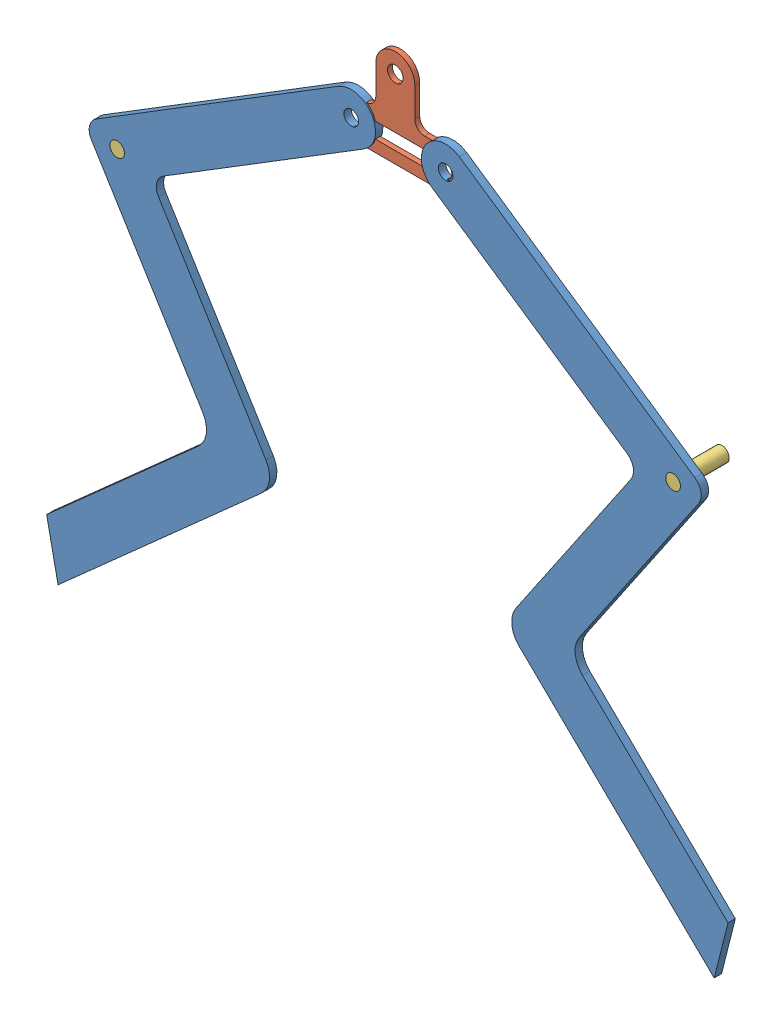
SolidWorks assembly Stopping Mechanism, configuration Default. Lengths in mm.
Overall size (215.56 131.52 10).
5 component instances, 3 part files, 10 mates.
Components (placement in the parent):
- Stop link-1: Stop link [Default] at (11.0323 -18.2674 0) x (0.716751 -0.69733 0) z (0 0 1) size (125 59.52 1.5)
- Linking link-2: Linking link [Default] at (-11.5672 55.4091 0) x (0 0 -1) z (1 0 0) size (1 20 28)
- Stop link-2: Stop link [Default] at (-35.6231 -17.6641 0) x (-0.746853 -0.664989 0) z (0 0 -1) size (125 59.52 1.5)
- pin-1: pin [Default] at (45.621 23.7108 -9.25) size (3 3 10)
- pin-2: pin [Default] at (-68.3239 25.801 0.75) x (-0.173648 0.984808 0) z (0 0 -1) size (3 3 10)
Mates (geometry in assembly coordinates):
- Concentric7: concentric aligned: cylinder of Stop link-1 through (45.621 23.7108 0.75) axis (0 0 -1) radius 1.5; cylinder of pin-1 through (45.621 23.7108 0.75) axis (0 0 -1) radius 1.5
- Concentric8: concentric aligned: cylinder of Stop link-2 through (-68.3239 25.801 -0.75) axis (0 0 1) radius 1.5; cylinder of pin-2 through (-68.3239 25.801 -9.25) axis (0 0 1) radius 1.5
- Coincident6: coincident aligned: plane of Stop link-2 through (-42.0815 -16.7198 0.75) normal (0 0 1); plane of pin-2 through (-68.3239 25.801 0.75) normal (0 0 1)
- Coincident7: coincident aligned: plane of Stop link-1 through (17.526 -17.6093 0.75) normal (0 0 1); plane of pin-1 through (45.621 23.7108 0.75) normal (0 0 1)
- Width1: width anti-aligned: plane of Stop link-1 through (17.526 -17.6093 0.75) normal (0 0 1); plane of Linking link-2 through (17.526 -17.6093 -0.75) normal (0 0 -1); plane of Stop link-1 through (-1.5672 55.4091 -0.5) normal (0 0 -1); plane of Linking link-2 through (-1.5672 55.4091 0.5) normal (0 0 1)
- Coincident15: coincident: line of assembly; point of Stop link-1; line of Linking link-2 through (-1.5672 55.4091 0) axis (-1 0 0)
- Coincident16: coincident: line of Linking link-2 through (-1.5672 55.4091 0) axis (-1 0 0)
- Coincident21: coincident anti-aligned: plane of Linking link-2 through (-11.5672 55.4091 0) normal (0 0 -1)
- Coincident23: coincident: point of Linking link-2; line of assembly
- Parallel5: parallel anti-aligned: plane of Linking link-2 through (-1.5672 51.4091 -0.5) normal (0 -1 0)
